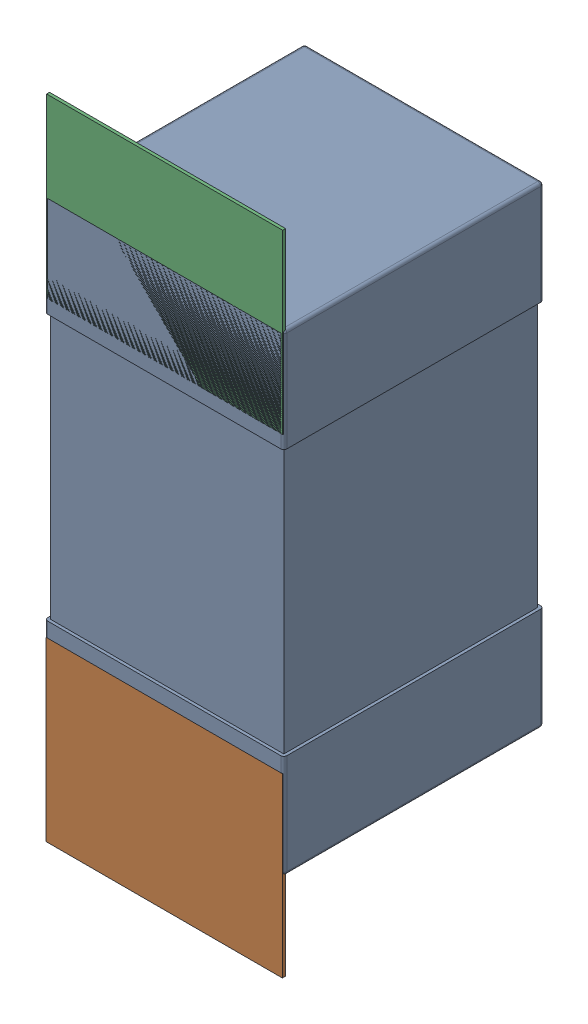
SolidWorks assembly C45, configuration Défaut. Lengths in mm.
Overall size (0.81 2.19 0.88).
5 component instances, 2 part files, 0 mates.
Components (placement in the parent):
- 0603_C-1: 0603_C [Défaut] at (13.3015 -8.5036 -2.0818) x (0 -1 0) z (0 0 -1) size (1.6 0.81 0.88)
- 8260087904-1: 8260087904 [Défaut] at (13.3015 -9.7536 -2.0918) size (0.8 0.6 0.01)
  - Extruded_1211-1: Extruded_1211 [Défaut] at origin size (0.8 0.6 0.01)
- 8260087904-2: 8260087904 [Défaut] at (13.3027 -8.1587 -2.0918) size (0.8 0.6 0.01)
  - Extruded_1211-1: Extruded_1211 [Défaut] at origin size (0.8 0.6 0.01)
